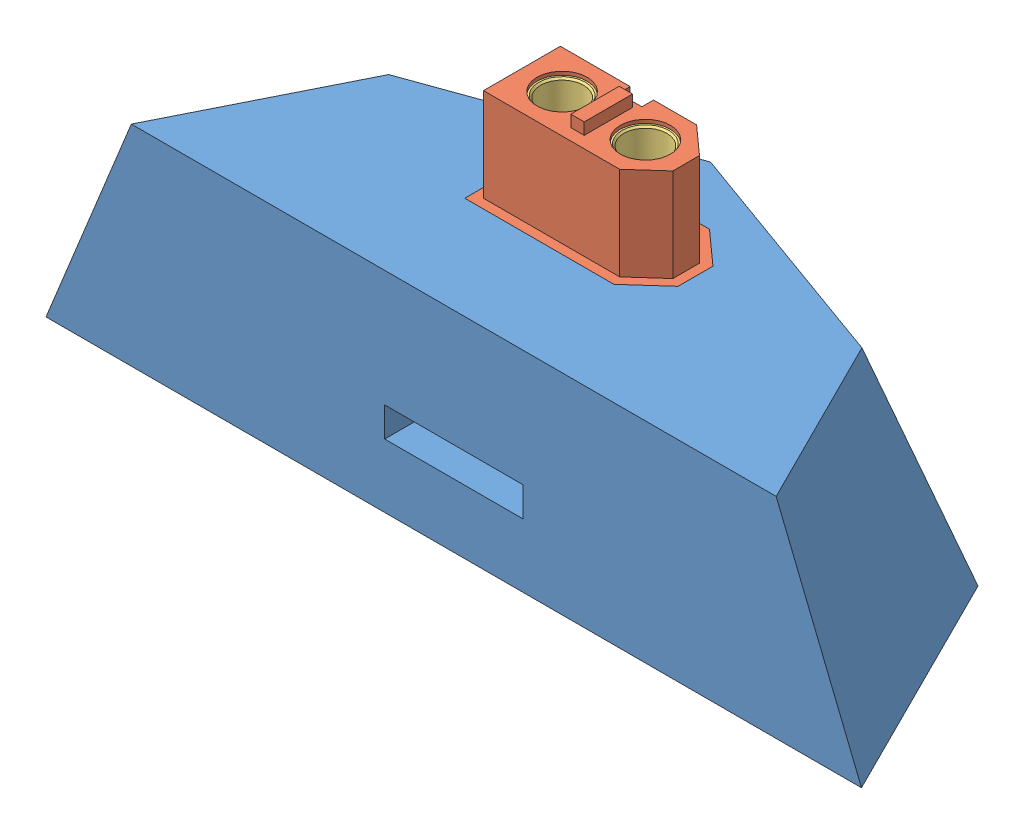
SolidWorks assembly portapik, configuration Predeterminado. Lengths in mm.
Overall size (70 28.3 29).
5 component instances, 3 part files, 6 mates.
Components (placement in the parent):
- portapickit_2-1: portapickit_2 [Predeterminado] at (-21.646 -0.2068 -0.5) size (70 18 29)
- XT-60_Femea-2: XT-60_Femea [Valor predeterminado] at (15.9111 18.5932 20.1296) x (1 0 0) z (0 1 0) size (16.3 8.2 28.3)
  - XT-60_Femea-1: XT-60_Femea [Valor predeterminado] at (-45.4071 14.4296 -8.6) size (16.3 8.2 16.8)
  - PinoXT-60_Femea-1: PinoXT-60_Femea [Valor predeterminado] at (-41.1571 18.5296 -13.1) x (0.019097 -0.999818 0) z (-0.999818 -0.019097 0) size (4.3 27 4.3)
  - PinoXT-60_Femea-2: PinoXT-60_Femea [Valor predeterminado] at (-34.0071 18.5296 -13.1) x (-0.00106 0.999999 0) z (0.999999 0.00106 0) size (4.3 27 4.3)
Mates (geometry in assembly coordinates):
- Ancho1: width aligned: plane of ? through (-29.496 15.9932 22.5) normal (-1 0 0); plane of ? through (-13.796 10.3932 22.5) normal (1 0 0); plane of portapickit_2-1 through (13.354 7.7932 14.5) normal (0.894427 0 -0.447214); plane of portapickit_2-1 through (-56.646 7.7932 14.5) normal (-0.894427 0 -0.447214)
- Distancia1: distance = 2.54 mm anti-aligned: plane of ? through (-29.496 7.7932 22.5) normal (0 -1 0); plane of portapickit_2-1 through (-21.646 5.2532 -0.5) normal (0 1 0)
- Coincidente2: coincident aligned: plane of portapickit_2-1 through (-56.646 7.7932 14.5) normal (0 0 1); plane of ? through (-29.496 7.7932 14.5) normal (0 0 1)
- Ancho2: width: plane of ? through (-29.496 23.5932 -2.5) normal (-1 0 0); plane of ? through (-13.796 23.5932 3.1) normal (1 0 0); plane of portapickit_2-1 through (-36.646 7.7932 -5.5) normal (1 0 0); plane of portapickit_2-1 through (-6.646 7.7932 -5.5) normal (-1 0 0)
- Coincidente3: coincident: line of portapickit_2-1 through (-6.646 7.7932 -2.5) axis (-1 0 0); plane of ? through (-16.696 23.5932 -2.5) normal (0 0 -1)
- Coincidente5: coincident aligned: plane of portapickit_2-1 through (-21.646 17.7932 -0.5) normal (0 1 0); plane of XT-60_Femea-2/XT-60_Femea-1 through (-29.496 17.7932 5.7) normal (0 1 0)
